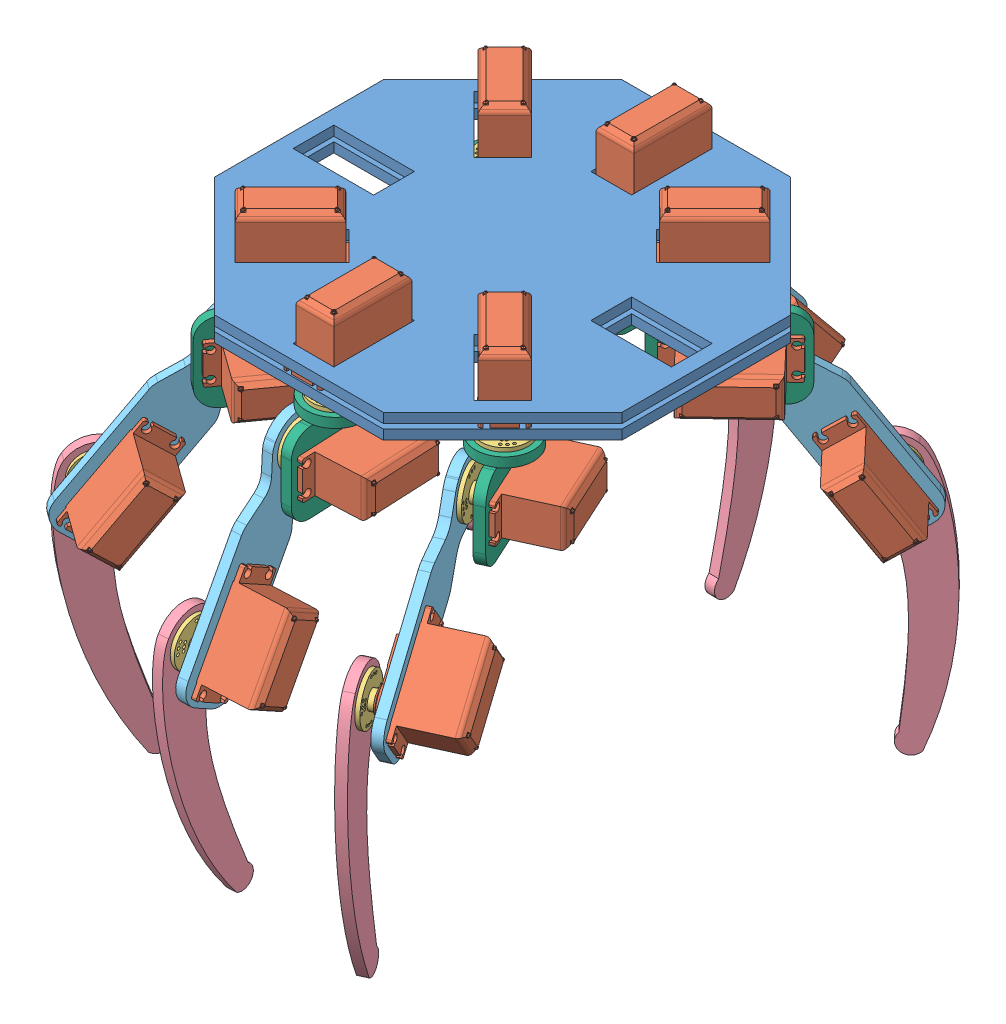
SolidWorks assembly Try2, configuration Default. Lengths in mm.
Overall size (365.48 270.12 428.65).
62 component instances, 6 part files, 21 mates.
Components (placement in the parent):
- base2-1: base2 [Default] at (43.3393 105.8489 144.3542) x (1 0 0) z (0 -1 0) size (210 210 5)
- right_leg-1: right_leg [Default] at (25.0596 97.4963 141.682) x (0.008727 0 -0.999962) z (0 -1 0) size (147.84 67.12 270.12) (flexible)
  - Standard Servo-1: Standard Servo [Default] at (-129.4277 39.3113 95.5096) x (-0.496978 0.027599 0.867324) z (0.86599 -0.048091 0.497744) size (53.74 42.63 19.57)
  - Horn-1: Horn [Default] at (-138.8047 -4.3359 104.4038) x (-0.96331 0.053496 -0.263005) z (-0.2626 0.014583 0.964795) size (24 5 24)
  - leg_3-1: leg_3 [Default] at (-139.0819 -9.3282 104.4038) x (0.507116 -0.028162 -0.861417) z (0.055448 0.998462 0) size (110.29 105.51 5)
  - leg_2-1: leg_2 [Default] at (-111.6142 8.9155 27.8938) x (0.496978 -0.027599 -0.867324) z (-0.055448 -0.998462 0) size (120 30 5)
  - Standard Servo-2: Standard Servo [Default] at (-82.5781 51.471 32.5966) x (-0.998462 0.055448 0) z (0 0 1) size (53.74 42.63 19.57)
  - Horn-2: Horn [Default] at (-96.1758 8.0582 31.0024) x (-0.993223 0.055157 0.102306) z (0.102149 -0.005673 0.994753) size (24 5 24)
  - leg_1-1: leg_1 [Default] at (-115.137 36.2229 6.2174) x (-0.998462 0.055448 0) z (0 0 1) size (61.5 30 46)
  - Standard Servo-3: Standard Servo [Default] at (-78.3263 21.2733 -37.8826) x (-0.999962 0.008727 0) z (0.008727 0.999962 0) size (53.74 42.63 19.57)
  - Horn-3: Horn [Default] at (-89.5094 19.7766 6.2174) x (0.993551 -0.113383 0) z (-0.113383 -0.993551 0) size (24 5 24)
- right_leg-2: right_leg [Default] at (32.3031 97.4963 129.5389) x (0.71325 0 -0.700909) z (0 -1 0) size (162.43 71.35 265.24) (flexible)
  - Standard Servo-1: Standard Servo [Default] at (-134.8561 45.0485 90.4791) x (-0.596585 0.101711 0.796079) z (0.784755 -0.133792 0.605193) size (53.74 42.63 19.57)
  - Horn-1: Horn [Default] at (-150.1825 2.9251 98.4062) x (-0.951071 0.162147 -0.263005) z (-0.259264 0.044202 0.964795) size (24 5 24)
  - leg_3-1: leg_3 [Default] at (-151.0228 -2.0038 98.4062) x (0.536033 -0.091388 -0.839236) z (0.168064 0.985776 0) size (110.29 105.51 5)
  - leg_2-1: leg_2 [Default] at (-112.1802 11.3975 25.9303) x (0.596585 -0.101711 -0.796079) z (-0.168064 -0.985776 0) size (120 30 5)
  - Standard Servo-2: Standard Servo [Default] at (-79.0365 50.4832 32.5966) x (-0.985776 0.168064 0) z (0 0 1) size (53.74 42.63 19.57)
  - Horn-2: Horn [Default] at (-97.4589 8.8877 31.0024) x (-0.980604 0.167182 0.102306) z (0.100851 -0.017194 0.994753) size (24 5 24)
  - leg_1-1: leg_1 [Default] at (-113.1116 39.0169 6.2174) x (-0.985776 0.168064 0) z (0 0 1) size (61.5 30 46)
  - Standard Servo-3: Standard Servo [Default] at (-78.3263 21.2733 -37.8826) x (-0.999962 0.008727 0) z (0.008727 0.999962 0) size (53.74 42.63 19.57)
  - Horn-3: Horn [Default] at (-89.5094 19.7766 6.2174) x (0.993551 -0.113383 0) z (-0.113383 -0.993551 0) size (24 5 24)
- right_leg-3: right_leg [Default] at (28.524 97.4963 155.3904) x (-0.700909 0 -0.71325) z (0 -1 0) size (165.94 120 251.75) (flexible)
  - Standard Servo-1: Standard Servo [Default] at (-154.4819 14.6677 77.3897) x (-0.742967 -0.26868 0.613035) z (0.576496 0.208479 0.790056) size (53.74 42.63 19.57)
  - Horn-1: Horn [Default] at (-148.7023 -30.1373 82.9776) x (-0.907291 -0.328104 -0.263005) z (-0.247329 -0.089442 0.964795) size (24 5 24)
  - leg_3-1: leg_3 [Default] at (-147.0019 -34.8392 82.9776) x (0.60413 0.218472 -0.766353) z (-0.340077 0.940398 0) size (110.29 105.51 5)
  - leg_2-1: leg_2 [Default] at (-103.3911 1.9215 22.2499) x (0.742967 0.26868 -0.613035) z (0.340077 -0.940398 0) size (120 30 5)
  - Standard Servo-2: Standard Servo [Default] at (-95.5466 51.6534 32.5966) x (-0.940398 -0.340077 0) z (0 0 1) size (53.74 42.63 19.57)
  - Horn-2: Horn [Default] at (-91.0531 6.3833 31.0024) x (-0.935463 -0.338293 0.102306) z (0.096209 0.034792 0.994753) size (24 5 24)
  - leg_1-1: leg_1 [Default] at (-119.5311 24.8705 6.2174) x (-0.940398 -0.340077 0) z (0 0 1) size (61.5 30 46)
  - Standard Servo-3: Standard Servo [Default] at (-78.3263 21.2733 -37.8826) x (-0.999962 0.008727 0) z (0.008727 0.999962 0) size (53.74 42.63 19.57)
  - Horn-3: Horn [Default] at (-89.5094 19.7766 6.2174) x (0.993551 -0.113383 0) z (-0.113383 -0.993551 0) size (24 5 24)
- left_leg-1: left_leg [Default] at (24.3621 97.4963 -12.8292) x (0 0 -1) z (0 -1 0) size (170.22 64.47 264.9) (flexible)
  - Standard Servo-1: Standard Servo [Default] at (-16.4098 37.6089 86.4616) x (0.635662 0.009367 0.771911) z (0.771827 0.011374 -0.635731) size (53.74 42.63 19.57)
  - Horn-1: Horn [Default] at (-9.8904 -6.3998 96.0971) x (-0.992835 -0.01463 0.118593) z (0.118581 0.001747 0.992943) size (24 5 24)
  - leg_3-1: leg_3 [Default] at (-9.8904 -6.3998 96.0971) x (-0.64527 -0.009509 -0.763896) z (0.014734 -0.999891 0) size (110.29 105.51 5)
  - leg_2-1: leg_2 [Default] at (-49.194 2.7608 25.3527) x (-0.635662 -0.009367 -0.771911) z (-0.014734 0.999891 0) size (120 30 5)
  - Standard Servo-2: Standard Servo [Default] at (-75.8092 51.474 29.4081) x (0.999891 0.014734 0) z (0 0 -1) size (53.74 42.63 19.57)
  - Horn-2: Horn [Default] at (-63.991 7.5433 31.0024) x (-0.986182 -0.014532 0.165026) z (0.165009 0.002432 0.986289) size (24 5 24)
  - leg_1-1: leg_1 [Default] at (-43.4589 5.0843 6.2174) x (0.999891 0.014734 0) z (0 0 1) size (61.5 30 46)
  - Standard Servo-3: Standard Servo [Default] at (-81.3467 18.098 -37.8826) x (1 0 0) z (0 -1 0) size (53.74 42.63 19.57)
  - Horn-3: Horn [Default] at (-70.177 19.6922 6.2174) x (1 0 0) z (0 -1 0) size (24 5 24)
- left_leg-2: left_leg [Default] at (141.0658 97.4963 19.7898) x (0.707107 0 -0.707107) z (0 -1 0) size (171.23 64.94 269.29) (flexible)
  - Standard Servo-1: Standard Servo [Default] at (-21.5648 38.0977 90.3852) x (0.566807 0.01489 0.823716) z (0.823432 0.021632 -0.567002) size (53.74 42.63 19.57)
  - Horn-1: Horn [Default] at (-15.3884 -5.8552 100.4898) x (-0.9926 -0.026076 0.118593) z (0.118553 0.003114 0.992943) size (24 5 24)
  - leg_3-1: leg_3 [Default] at (-15.3884 -5.8552 100.4898) x (-0.725357 -0.019055 -0.688109) z (0.026261 -0.999655 0) size (110.29 105.51 5)
  - leg_2-1: leg_2 [Default] at (-48.5691 3.0152 26.6398) x (-0.566807 -0.01489 -0.823716) z (-0.026261 0.999655 0) size (120 30 5)
  - Standard Servo-2: Standard Servo [Default] at (-76.1753 51.4069 29.4081) x (0.999655 0.026261 0) z (0 0 -1) size (53.74 42.63 19.57)
  - Horn-2: Horn [Default] at (-63.8513 7.6155 31.0024) x (-0.985949 -0.025901 0.165026) z (0.16497 0.004334 0.986289) size (24 5 24)
  - leg_1-1: leg_1 [Default] at (-43.2923 5.3933 6.2174) x (0.999655 0.026261 0) z (0 0 1) size (61.5 30 46)
  - Standard Servo-3: Standard Servo [Default] at (-81.3467 18.098 -37.8826) x (1 0 0) z (0 -1 0) size (53.74 42.63 19.57)
  - Horn-3: Horn [Default] at (-70.177 19.6922 6.2174) x (1 0 0) z (0 -1 0) size (24 5 24)
- left_leg-3: left_leg [Default] at (-81.2251 97.4963 46.6277) x (-0.707107 0 -0.707107) z (0 -1 0) size (180.3 79.63 254.99) (flexible)
  - Standard Servo-1: Standard Servo [Default] at (-17.281 56.3077 78.3828) x (0.705479 0.246446 0.664502) z (0.627327 0.219145 -0.747286) size (53.74 42.63 19.57)
  - Horn-1: Horn [Default] at (4.1425 17.0782 86.9964) x (-0.937393 -0.327461 0.118593) z (0.111959 0.039111 0.992943) size (24 5 24)
  - leg_3-1: leg_3 [Default] at (4.1425 17.0782 86.9964) x (-0.558339 -0.195045 -0.806359) z (0.329788 -0.944055 0) size (110.29 105.51 5)
  - leg_2-1: leg_2 [Default] at (-45.9106 9.9089 23.147) x (-0.705479 -0.246446 -0.664502) z (-0.329788 0.944055 0) size (120 30 5)
  - Standard Servo-2: Standard Servo [Default] at (-85.5589 48.0682 29.4081) x (0.944055 0.329788 0) z (0 0 -1) size (53.74 42.63 19.57)
  - Horn-2: Horn [Default] at (-60.4705 10.119 31.0024) x (-0.931111 -0.325266 0.165026) z (0.155794 0.054424 0.986289) size (24 5 24)
  - leg_1-1: leg_1 [Default] at (-40.2128 14.2708 6.2174) x (0.944055 0.329788 0) z (0 0 1) size (61.5 30 46)
  - Standard Servo-3: Standard Servo [Default] at (-81.3467 18.098 -37.8826) x (1 0 0) z (0 -1 0) size (53.74 42.63 19.57)
  - Horn-3: Horn [Default] at (-70.177 19.6922 6.2174) x (1 0 0) z (0 -1 0) size (24 5 24)
- base2-2: base2 [Default] at (43.3393 113.3089 144.3542) x (1 0 0) z (0 -1 0) size (210 210 5)
Mates (geometry in assembly coordinates):
- Coincident1: coincident: plane of assembly; plane of assembly; plane of base2-1 through (53.8393 100.8489 200.3542) normal (-1 0 0); plane of right_leg-1/Standard Servo-3 through (53.8393 100.0089 201.5342) normal (1 0 0)
- Coincident2: coincident: plane of assembly; plane of assembly; plane of base2-1 through (53.8393 100.8489 241.8542) normal (0 0 -1); plane of right_leg-1/Standard Servo-3 through (34.2693 100.0089 241.8542) normal (0 0 1)
- Coincident3: coincident: plane of base2-1 through (90.3619 100.8489 176.5276) normal (-0.707107 0 0.707107); plane of right_leg-3/Standard Servo-3 through (91.1963 100.0089 177.3619) normal (0.707107 0 -0.707107)
- Coincident5: coincident: plane of base2-1 through (119.7068 100.8489 205.8725) normal (-0.707107 0 -0.707107); plane of right_leg-3/Standard Servo-3 through (105.8687 100.0089 219.7106) normal (0.707107 0 0.707107)
- Coincident6: coincident: plane of base2-1 through (11.1659 100.8489 191.3768) normal (-0.707107 0 -0.707107); plane of right_leg-2/Standard Servo-3 through (10.3315 100.0089 192.2112) normal (0.707107 0 0.707107)
- Coincident7: coincident: plane of base2-1 through (-18.179 100.8489 220.7217) normal (0.707107 0 -0.707107); plane of right_leg-2/Standard Servo-3 through (-32.0171 100.0089 206.8837) normal (-0.707107 0 0.707107)
- Coincident8: coincident: plane of base2-1 through (90.3619 100.8489 112.1808) normal (-0.707107 0 -0.707107); plane of left_leg-2/Standard Servo-3 through (91.1963 100.0089 111.3465) normal (0.707107 0 0.707107)
- Coincident9: coincident: plane of base2-1 through (104.8576 100.8489 67.9867) normal (-0.707107 0 0.707107); plane of left_leg-2/Standard Servo-3 through (119.7068 100.0089 82.8359) normal (0.707107 0 -0.707107)
- Coincident10: coincident: plane of base2-1 through (53.8393 100.8489 88.3542) normal (-1 0 0); plane of left_leg-1/Standard Servo-3 through (53.8393 100.0089 87.1742) normal (1 0 0)
- Coincident11: coincident: plane of base2-1 through (32.8393 100.8489 46.8542) normal (0 0 1); plane of left_leg-1/Standard Servo-3 through (53.8393 100.0089 46.8542) normal (0 0 -1)
- Coincident12: coincident: plane of base2-1 through (11.1659 100.8489 97.3316) normal (-0.707107 0 0.707107); plane of left_leg-3/Standard Servo-3 through (10.3315 100.0089 96.4972) normal (0.707107 0 -0.707107)
- Coincident13: coincident: plane of base2-1 through (-33.0282 100.8489 82.8359) normal (0.707107 0 0.707107); plane of left_leg-3/Standard Servo-3 through (-18.179 100.0089 67.9867) normal (-0.707107 0 -0.707107)
- Coincident14: coincident: plane of assembly; plane of assembly; plane of base2-1 through (43.3393 105.8489 144.3542) normal (0 1 0); plane of right_leg-1/Standard Servo-3 through (53.8393 105.8489 248.5642) normal (0 -1 0)
- Coincident15: coincident: plane of base2-1 through (43.3393 105.8489 144.3542) normal (0 1 0); plane of right_leg-3/Standard Servo-3 through (124.4515 105.8489 210.6172) normal (0 -1 0)
- Coincident16: coincident: plane of base2-1 through (43.3393 105.8489 144.3542) normal (0 1 0); plane of right_leg-2/Standard Servo-3 through (-22.9237 105.8489 225.4664) normal (0 -1 0)
- Coincident17: coincident: plane of base2-1 through (43.3393 105.8489 144.3542) normal (0 1 0); plane of left_leg-2/Standard Servo-3 through (110.6134 105.8489 64.2531) normal (0 -1 0)
- Coincident18: coincident: plane of base2-1 through (43.3393 105.8489 144.3542) normal (0 1 0); plane of left_leg-1/Standard Servo-3 through (34.2693 105.8489 40.1442) normal (0 -1 0)
- Coincident19: coincident: plane of base2-1 through (43.3393 105.8489 144.3542) normal (0 1 0); plane of left_leg-3/Standard Servo-3 through (-36.7618 105.8489 77.0801) normal (0 -1 0)
- Coincident20: coincident: plane of assembly; plane of assembly; plane of base2-1 through (148.3393 100.8489 100.8618) normal (1 0 0); plane of base2-2 through (148.3393 108.3089 100.8618) normal (1 0 0)
- Coincident21: coincident: plane of assembly; plane of assembly; plane of base2-1 through (86.8317 100.8489 249.3542) normal (0 0 1); plane of base2-2 through (86.8317 108.3089 249.3542) normal (0 0 1)
- Coincident22: coincident: plane of right_leg-3/Standard Servo-3 through (110.6134 108.3089 224.4553) normal (0 1 0); plane of base2-2 through (43.3393 108.3089 144.3542) normal (0 -1 0)
